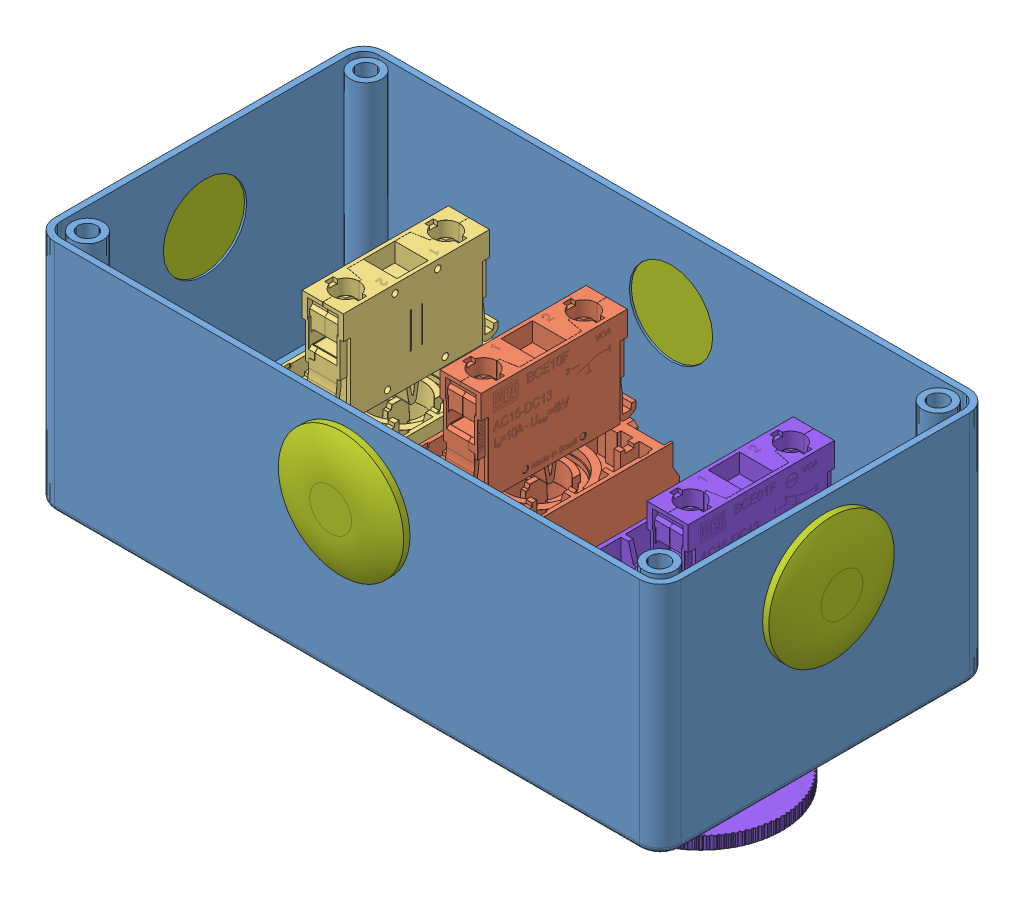
SolidWorks assembly completo, configuration Default. Lengths in mm.
Overall size (158 84.35 87).
11 component instances, 8 part files, 26 mates.
Components (placement in the parent):
- caixa-botoes-1: caixa-botoes [Default] at (-6.3493 -13.6366 12.6149) size (150 56.2 79)
- botoeira-red-2: botoeira-red [Default] at (18.2591 19.1084 7.9689) x (1 0 0) z (0 -1 0) size (30.5 46.9 61.5)
- botoeira-3: botoeira [Default] at (-63.9577 19.1084 17.261) x (-1 0 0) z (0 -1 0) size (30.5 46.9 61.5)
- placa liga-1: placa liga [Default] at (-39.3493 -13.3866 43.4649) x (1 0 0) z (0 -1 0) size (22.5 15 1)
- desliga-1: desliga [Default] at (-6.3493 -13.3866 43.4649) x (1 0 0) z (0 -1 0) size (22.5 15 1)
- emrg-1: emrg [Default] at (33.6507 -13.3866 43.4649) x (1 0 0) z (0 -1 0) size (22.5 15 1)
- botao-1: botao [Default] at (-80.5424 24.0634 17.6149) x (0 0.300013 -0.953935) z (0 0.953935 0.300013) size (30 5 30)
- botao-2: botao [Default] at (-6.4788 24.0634 -20.8851) x (-0.476054 -0.879416 0) z (0.879416 -0.476054 0) size (30 5 30)
- botao-3: botao [Default] at (67.4576 24.0634 17.6149) x (0 0.775785 -0.630997) z (0 -0.630997 -0.775785) size (30 5 30)
- botao-4: botao [Default] at (-6.4788 24.0634 56.1149) x (-0.776604 0.629989 0) z (0.629989 0.776604 0) size (30 5 30)
- SW_BOTÃO DE EMERGÊNCIA (CEW-BEGM-0100000)-1: SW_BOTÃO DE EMERGÊNCIA (CEW-BEGM-0100000) [Valor predeterminado] at (64.0763 18.3021 6.0881) x (1 0 0) z (0 -1 0) size (39.36 46.9 71.88)
Mates (geometry in assembly coordinates):
- Concentric9: concentric anti-aligned: cylinder of caixa-botoes-1 through (-6.3493 42.5634 12.6149) axis (0 -1 0) radius 11.25; cylinder of botoeira-red-2 through (-6.3493 6.6434 12.6149) axis (0 1 0) radius 10.6
- Parallel3: parallel anti-aligned: plane of caixa-botoes-1 through (-7.9493 42.5634 0.3649) normal (0 0 1); plane of botoeira-red-2 through (-6.3493 6.6434 0.7149) normal (0 0 -1)
- Coincident8: coincident anti-aligned: plane of caixa-botoes-1 through (-76.5424 -13.6366 -16.8851) normal (0 -1 0); circle of botoeira-red-2
- Concentric11: concentric anti-aligned: cylinder of caixa-botoes-1 through (-39.3493 42.5634 12.6149) axis (0 -1 0) radius 11.25; cylinder of botoeira-3 through (-39.3493 6.6434 12.6149) axis (0 1 0) radius 10.6
- Coincident10: coincident anti-aligned: plane of caixa-botoes-1 through (-76.5424 -13.6366 -16.8851) normal (0 -1 0); circle of botoeira-3
- Parallel4: parallel aligned: plane of caixa-botoes-1 through (-80.0424 42.5634 -16.8851) normal (1 0 0); plane of botoeira-3 through (-34.4243 35.1453 12.6149) normal (1 0 0)
- Coincident14: coincident anti-aligned: plane of caixa-botoes-1 through (-28.0993 -13.3866 50.9649) normal (0 -1 0); plane of placa liga-1 through (-50.5993 -13.3866 50.9649) normal (0 1 0)
- Coincident15: coincident anti-aligned: plane of caixa-botoes-1 through (-28.0993 -13.3866 35.9649) normal (-1 0 0); plane of placa liga-1 through (-28.0993 -13.8866 35.9649) normal (1 0 0)
- Coincident16: coincident anti-aligned: plane of caixa-botoes-1 through (-50.5993 -13.3866 35.9649) normal (0 0 1); plane of placa liga-1 through (-28.0993 -13.8866 35.9649) normal (0 0 -1)
- Parallel7: parallel anti-aligned: plane of caixa-botoes-1 through (4.9007 -13.3866 50.9649) normal (0 -1 0); plane of desliga-1 through (-17.5993 -13.3866 50.9649) normal (0 1 0)
- Coincident21: coincident anti-aligned: plane of caixa-botoes-1 through (-17.5993 -13.3866 35.9649) normal (0 0 1); plane of desliga-1 through (4.9007 -13.8866 35.9649) normal (0 0 -1)
- Coincident22: coincident anti-aligned: plane of caixa-botoes-1 through (-17.5993 -13.3866 35.9649) normal (1 0 0); plane of desliga-1 through (-17.5993 -13.8866 35.9649) normal (-1 0 0)
- Coincident24: coincident anti-aligned: plane of caixa-botoes-1 through (4.9007 -13.3866 50.9649) normal (0 -1 0); plane of desliga-1 through (-17.5993 -13.3866 50.9649) normal (0 1 0)
- Coincident25: coincident anti-aligned: plane of caixa-botoes-1 through (44.9007 -13.3866 35.9649) normal (0 0 1); plane of emrg-1 through (44.9007 -13.8866 35.9649) normal (0 0 -1)
- Coincident27: coincident anti-aligned: plane of caixa-botoes-1 through (22.4007 -13.3866 50.9649) normal (0 -1 0); plane of emrg-1 through (22.4007 -13.3866 50.9649) normal (0 1 0)
- Coincident28: coincident anti-aligned: plane of caixa-botoes-1 through (44.9007 -13.3866 35.9649) normal (-1 0 0); plane of emrg-1 through (44.9007 -13.8866 35.9649) normal (1 0 0)
- Concentric14: concentric anti-aligned: cylinder of caixa-botoes-1 through (68.4576 24.0634 17.6149) axis (-1 0 0) radius 10; cylinder of botao-1 through (-80.5424 24.0634 17.6149) axis (1 0 0) radius 10
- Coincident29: coincident anti-aligned: plane of caixa-botoes-1 through (-81.5424 42.5634 -16.8851) normal (-1 0 0); plane of botao-1 through (-81.5424 27.0635 8.0756) normal (1 0 0)
- Concentric15: concentric anti-aligned: cylinder of caixa-botoes-1 through (-6.4788 24.0634 57.1149) axis (0 0 -1) radius 10; cylinder of botao-2 through (-6.4788 24.0634 -20.8851) axis (0 0 1) radius 10
- Coincident30: coincident anti-aligned: plane of caixa-botoes-1 through (-76.5424 42.5634 -21.8851) normal (0 0 -1); plane of botao-2 through (-11.2394 15.2693 -21.8851) normal (0 0 1)
- Concentric16: concentric aligned: cylinder of caixa-botoes-1 through (68.4576 24.0634 17.6149) axis (-1 0 0) radius 10; cylinder of botao-3 through (67.4576 24.0634 17.6149) axis (-1 0 0) radius 10
- Coincident31: coincident anti-aligned: plane of caixa-botoes-1 through (68.4576 42.5634 -16.8851) normal (1 0 0); plane of botao-3 through (68.4576 31.8213 11.305) normal (-1 0 0)
- Concentric17: concentric aligned: cylinder of caixa-botoes-1 through (-6.4788 24.0634 57.1149) axis (0 0 -1) radius 10; cylinder of botao-4 through (-6.4788 24.0634 56.1149) axis (0 0 -1) radius 10
- Coincident32: coincident anti-aligned: plane of caixa-botoes-1 through (-76.5424 42.5634 57.1149) normal (0 0 1); plane of botao-4 through (-14.2449 30.3633 57.1149) normal (0 0 -1)
- Concêntrico1: concentric: cylinder of caixa-botoes-1 through (33.6507 42.5634 12.6149) axis (0 -1 0) radius 11.25; cylinder of SW_BOTÃO DE EMERGÊNCIA (CEW-BEGM-0100000)-1 through (33.6507 13.8134 12.6149) axis (0 1 0) radius 13.9
- Coincidente1: coincident anti-aligned: plane of caixa-botoes-1 through (-76.5424 -13.6366 -16.8851) normal (0 -1 0); plane of SW_BOTÃO DE EMERGÊNCIA (CEW-BEGM-0100000)-1 through (33.6507 -13.6366 24.1149) normal (0 1 0)
